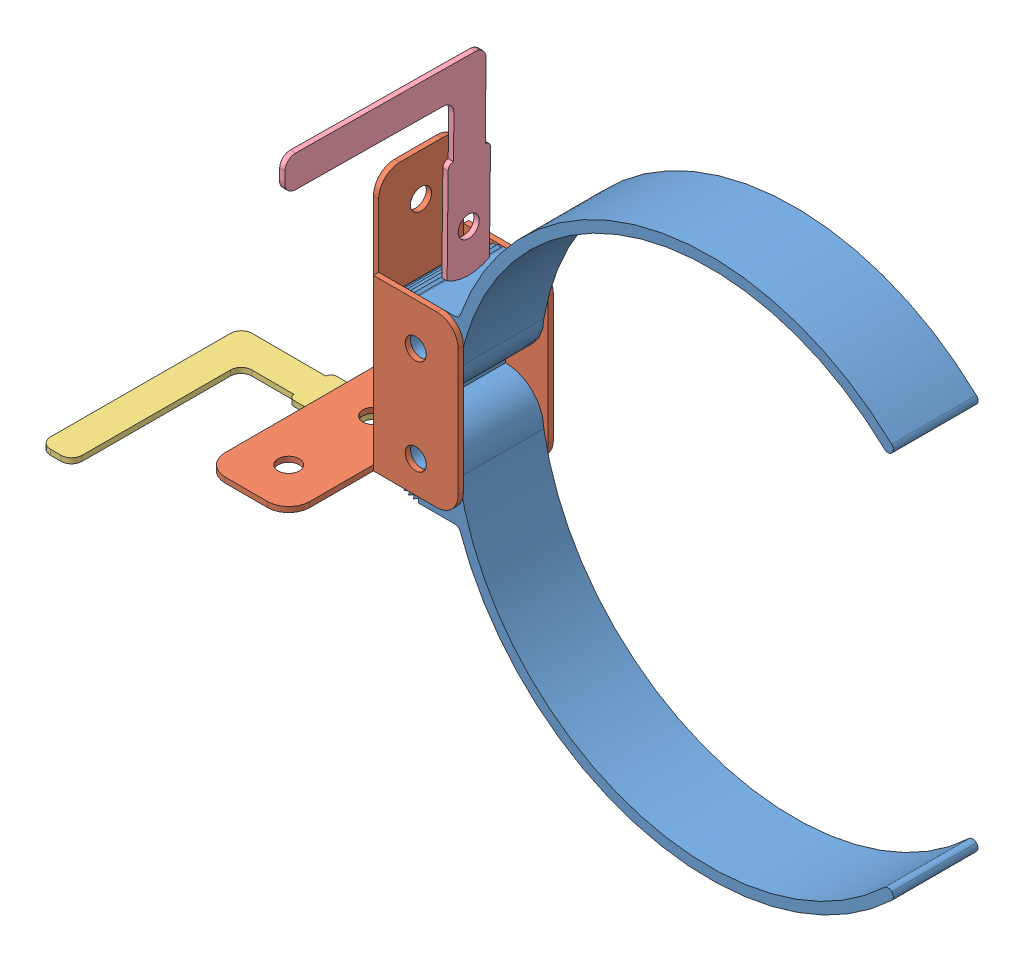
SolidWorks assembly New Merged Leg Piece, configuration Default. Lengths in mm.
Overall size (213.17 165.69 93.8).
5 component instances, 4 part files, 8 mates.
Components (placement in the parent):
- Ratchet Clamp-1: Ratchet Clamp [Default] at (-14.1466 61.1398 110.7835) size (154.32 79.38 25.4)
- Ratchet Clamp-2: Ratchet Clamp [Default] at (-14.1466 32.5648 136.1835) x (1 0 0) z (0 0 -1) size (154.32 79.38 25.4)
- New Merged Plate-2: New Merged Plate [Default] at (-26.8466 23.0398 110.7835) x (-1 0 0) z (0 0 -1) size (52.39 77.79 76.2)
- Plate Tab-2: Plate Tab [Default] at (-47.4715 19.8648 117.1208) x (-0.999998 0 -0.001994) z (0.001994 0 -0.999998) size (69.85 1.59 61.91)
- Plate Tab 2-2: Plate Tab 2 [Default] at (-14.1466 92.8213 117.0657) x (0 0.999942 -0.010737) z (0 -0.010737 -0.999942) size (57.15 1.59 61.91)
Mates (geometry in assembly coordinates):
- Coincident1: coincident anti-aligned: plane of Ratchet Clamp-1 through (-14.1466 61.1398 136.1835) normal (0 0 1); plane of New Merged Plate-2 through (-26.8466 23.0398 136.1835) normal (0 0 -1)
- Coincident2: coincident anti-aligned: plane of Ratchet Clamp-2 through (-14.1466 32.5648 136.1835) normal (0 0 1); plane of New Merged Plate-2 through (-26.8466 23.0398 136.1835) normal (0 0 -1)
- Concentric1: concentric anti-aligned: cylinder of Ratchet Clamp-2 through (-14.1466 32.5648 110.7835) axis (0 0 1) radius 3.175; cylinder of New Merged Plate-2 through (-14.1466 32.5648 137.771) axis (0 0 -1) radius 3.175
- Concentric2: concentric aligned: cylinder of Ratchet Clamp-1 through (-14.1466 61.1398 136.1835) axis (0 0 -1) radius 3.175; cylinder of New Merged Plate-2 through (-14.1466 61.1398 137.771) axis (0 0 -1) radius 3.175
- Concentric3: concentric anti-aligned: cylinder of New Merged Plate-2 through (-41.1341 21.4523 123.4835) axis (0 1 0) radius 3.175; cylinder of Plate Tab-2 through (-41.1341 21.4523 123.4835) axis (0 -1 0) radius 3.175
- Coincident3: coincident anti-aligned: plane of New Merged Plate-2 through (-26.8466 21.4523 110.7835) normal (0 -1 0); plane of Plate Tab-2 through (-47.4715 21.4523 117.1208) normal (0 1 0)
- Distance4: distance = 12.7 mm anti-aligned: plane of Plate Tab 2-2 through (-14.1466 92.8213 117.0657) normal (-1 0 0); plane of New Merged Plate-2 through (-26.8466 23.0398 110.7835) normal (1 0 0)
- Concentric6: concentric anti-aligned: cylinder of New Merged Plate-2 through (-28.4341 86.5398 123.4835) axis (1 0 0) radius 3.175; cylinder of Plate Tab 2-2 through (-12.5591 86.5398 123.4835) axis (-1 0 0) radius 3.175
